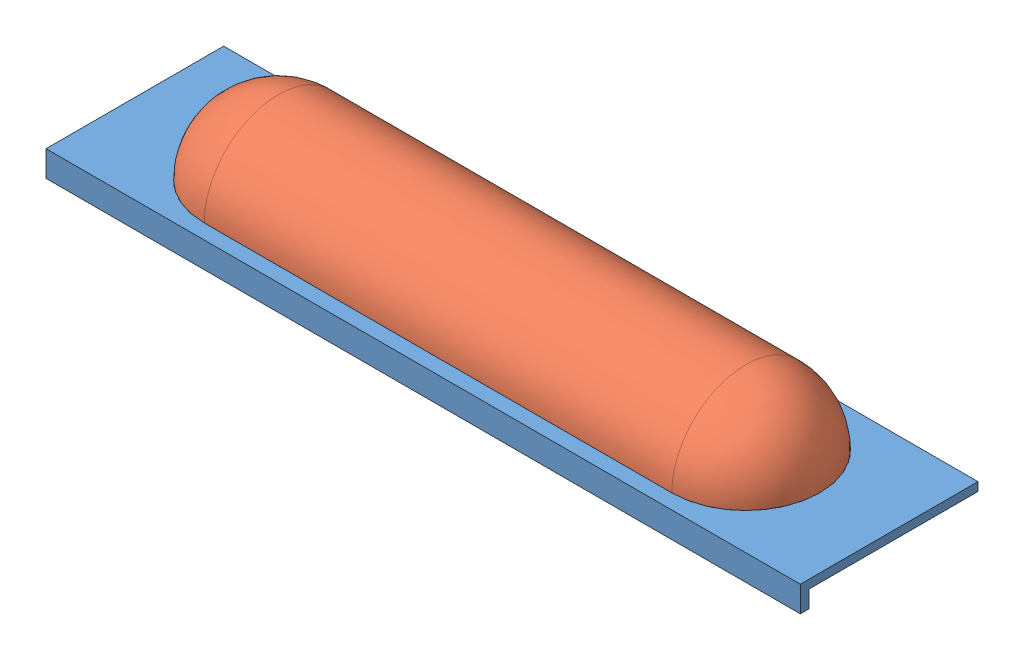
SolidWorks assembly oblivionhouseswimmingpoolassembly-mpang, configuration Default. Lengths in mm.
Overall size (9680 1280 2280).
3 component instances, 3 part files, 5 mates.
Components (placement in the parent):
- oblivionhousepoolledge-mpang-1: oblivionhousepoolledge-mpang [Default] at origin size (9680 330 2280)
- oblivionhouseswimmingpoolbottom-mpang-1: oblivionhouseswimmingpoolbottom-mpang [Default] at (0 110 0) x (1 0 0) z (0 -1 0) size (7900 1900 950)
- oblivionhouseswimmingpooltop-mpang-1: oblivionhouseswimmingpooltop-mpang [Default] at origin size (7900 110 1900)
Mates (geometry in assembly coordinates):
- Coincident7: coincident anti-aligned: line of oblivionhousepoolledge-mpang-1 through (3000 110 -950) axis (-1 0 0); line of oblivionhouseswimmingpoolbottom-1 through (-3000 110 -950) axis (1 0 0)
- Coincident8: coincident aligned: circle of oblivionhousepoolledge-mpang-1; circle of oblivionhouseswimmingpoolbottom-1
- Concentric1: concentric anti-aligned: cylinder of oblivionhousepoolledge-mpang-1 through (-3000 0 0) axis (0 1 0) radius 950; cylinder of oblivionhouseswimmingpooltop-mpang-1 through (-3000 110 0) axis (0 -1 0) radius 950
- Coincident11: coincident anti-aligned: plane of oblivionhousepoolledge-mpang-1 through (-3000 0 -950) normal (0 0 1); plane of oblivionhouseswimmingpooltop-mpang-1 through (3000 110 -950) normal (0 0 -1)
- Coincident12: coincident anti-aligned: plane of oblivionhouseswimmingpoolbottom-mpang-1 through (-3000 110 0) normal (0 -1 0); plane of oblivionhouseswimmingpooltop-mpang-1 through (-3000 110 0) normal (0 1 0)
